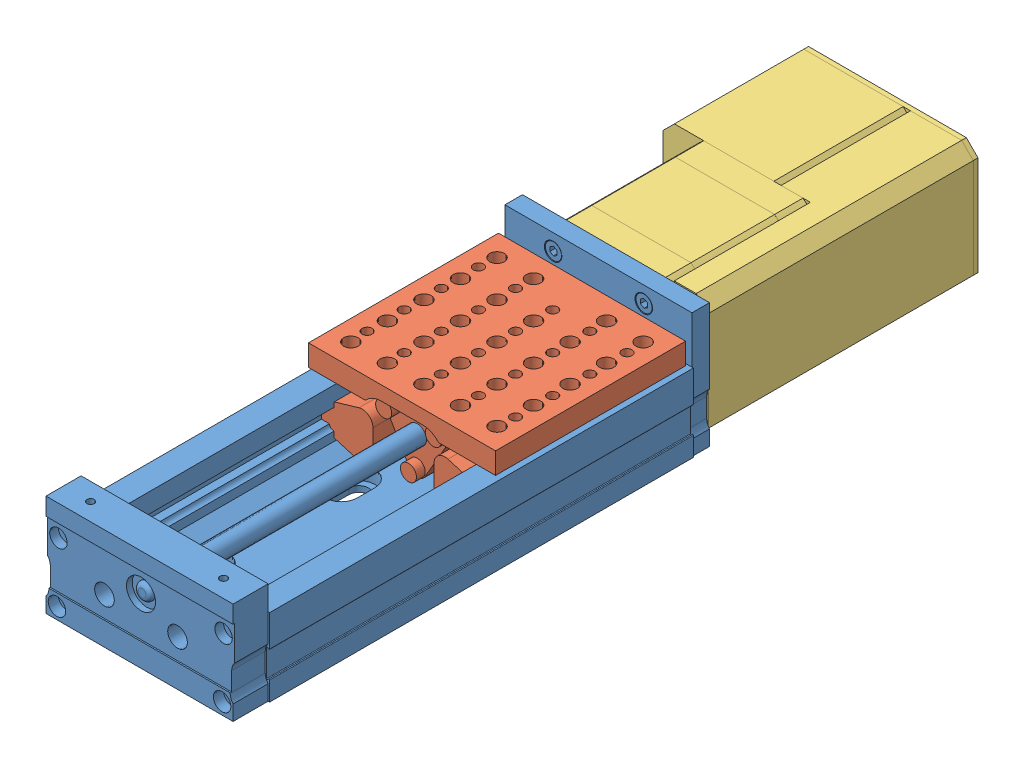
SolidWorks assembly LSQ, configuration LSQ075x-T3A. Lengths in mm.
Overall size (65 43.1 260.61).
3 component instances, 3 part files, 6 mates.
Components (placement in the parent):
- LSQ_base^LSQ-1: LSQ_base^LSQ [LSQ075] at origin size (65 43.1 163) (virtual)
- LSQ_carriage^LSQ-1: LSQ_carriage^LSQ [Standard] at origin size (64 27.1 65) (virtual)
- NMS17_motor^LSQ-1: NMS17_motor^LSQ [LSQ-T3A] at (0 22.08 0) size (62 42 117.61) (virtual)
Mates (geometry in assembly coordinates):
- Coincident1: coincident aligned: plane of LSQ_carriage^LSQ-1 through (0 0 0) normal (1 0 0); plane of assembly through (0 0 0) normal (1 0 0)
- Coincident2: coincident aligned: plane of LSQ_carriage^LSQ-1 through (0 0 0) normal (0 1 0); plane of assembly through (0 0 0) normal (0 1 0)
- LimitDistance1: limit distance = 0 mm aligned: plane of LSQ_carriage^LSQ-1 through (0 0 0) normal (0 0 1); plane of assembly through (0 0 0) normal (0 0 1)
- Coincident4: coincident aligned: plane of NMS17_motor^LSQ-1 through (0 22.08 0) normal (0 0 1); plane of assembly through (0 0 0) normal (0 0 1)
- Coincident5: coincident aligned: plane of NMS17_motor^LSQ-1 through (0 22.08 0) normal (1 0 0); plane of assembly through (0 0 0) normal (1 0 0)
- Concentric1: concentric: cylinder of LSQ_base^LSQ-1 through (0 22.08 6) axis (0 0 -1) radius 6.5; point of NMS17_motor^LSQ-1
